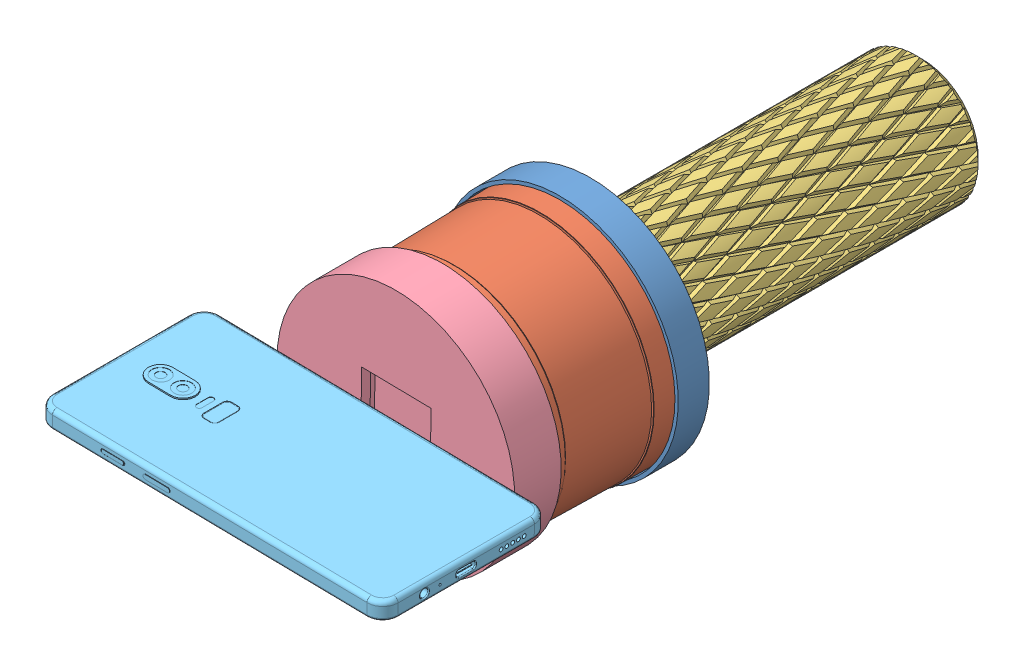
SolidWorks assembly velodyne holder assembly, configuration Default. Lengths in mm.
Overall size (236.43 136.46 328.55).
5 component instances, 5 part files, 11 mates.
Components (placement in the parent):
- velodyne holder-1: velodyne holder [Default] at (-154.2736 -82.0842 2) x (0 1 0) z (1 0 0) size (107 14 107)
- 86-0101 REV B ENVELOPE, VLP-16-1: 86-0101 REV B ENVELOPE, VLP-16 [Default] at (-154.2736 -82.0842 4) x (0 -1 0) z (-1 0 0) size (103.62 72.75 103.27)
- knurled grip-1: knurled grip [Default] at (-154.2736 -82.0842 -1) x (-0.744556 -0.66756 0) z (0.66756 -0.744556 0) size (60 151 60)
- velodyne holder - boven-1: velodyne holder - boven [Default] at (-154.2736 -82.0842 78.7463) x (0.999865 -0.016461 0) z (0.016461 0.999865 0) size (107 21 107)
- oneplus-1: oneplus [Default] at (-148.459 -64.1775 139.6463) x (0.999865 -0.016461 0) z (0 0 -1) size (155.7 8.35 76.1)
Mates (geometry in assembly coordinates):
- Concentric4: concentric anti-aligned: circle of velodyne holder-1; circle of 86-0101 REV B ENVELOPE, VLP-16-1
- Concentric5: concentric anti-aligned: circle of velodyne holder-1; circle of 86-0101 REV B ENVELOPE, VLP-16-1
- Coincident1: coincident anti-aligned: plane of velodyne holder-1 through (-154.2736 -82.0842 4) normal (0 0 1); plane of 86-0101 REV B ENVELOPE, VLP-16-1 through (-154.2736 -30.4481 4) normal (0 0 -1)
- Concentric6: concentric aligned: circle of velodyne holder-1; circle of knurled grip-1
- Concentric7: concentric anti-aligned: circle of velodyne holder-1; circle of knurled grip-1
- Coincident2: coincident anti-aligned: plane of velodyne holder-1 through (-154.2736 -82.0842 0) normal (0 0 -1); plane of knurled grip-1 through (-154.2736 -82.0842 0) normal (0 0 1)
- Concentric10: concentric aligned: cone of 86-0101 REV B ENVELOPE, VLP-16-1 through (-154.2736 -82.0842 74.8723) axis (0 0 1); cylinder of velodyne holder - boven-1 through (-154.2736 -82.0842 66.7463) axis (0 0 1) radius 51.6
- Coincident4: coincident anti-aligned: circle of 86-0101 REV B ENVELOPE, VLP-16-1; plane of velodyne holder - boven-1 through (-154.2736 -82.0842 76.7463) normal (0 0 -1)
- Distance1: distance = 14.2 mm anti-aligned: plane of oneplus-1 through (-226.426 -70.645 101.9463) normal (0 0 -1); plane of velodyne holder - boven-1 through (-154.2736 -82.0842 87.7463) normal (0 0 1)
- Coincident10: coincident anti-aligned: plane of velodyne holder - boven-1 through (-135.9797 -64.3829 79.2463) normal (-0.016461 -0.999865 0); plane of oneplus-1 through (-148.459 -64.1775 139.6463) normal (0.016461 0.999865 0)
- Distance2: distance = 54.331 mm anti-aligned: plane of oneplus-1 through (-226.426 -70.645 101.9463) normal (-0.999865 0.016461 0); plane of velodyne holder - boven-1 through (-171.9748 -63.7903 79.2463) normal (0.999865 -0.016461 0)
